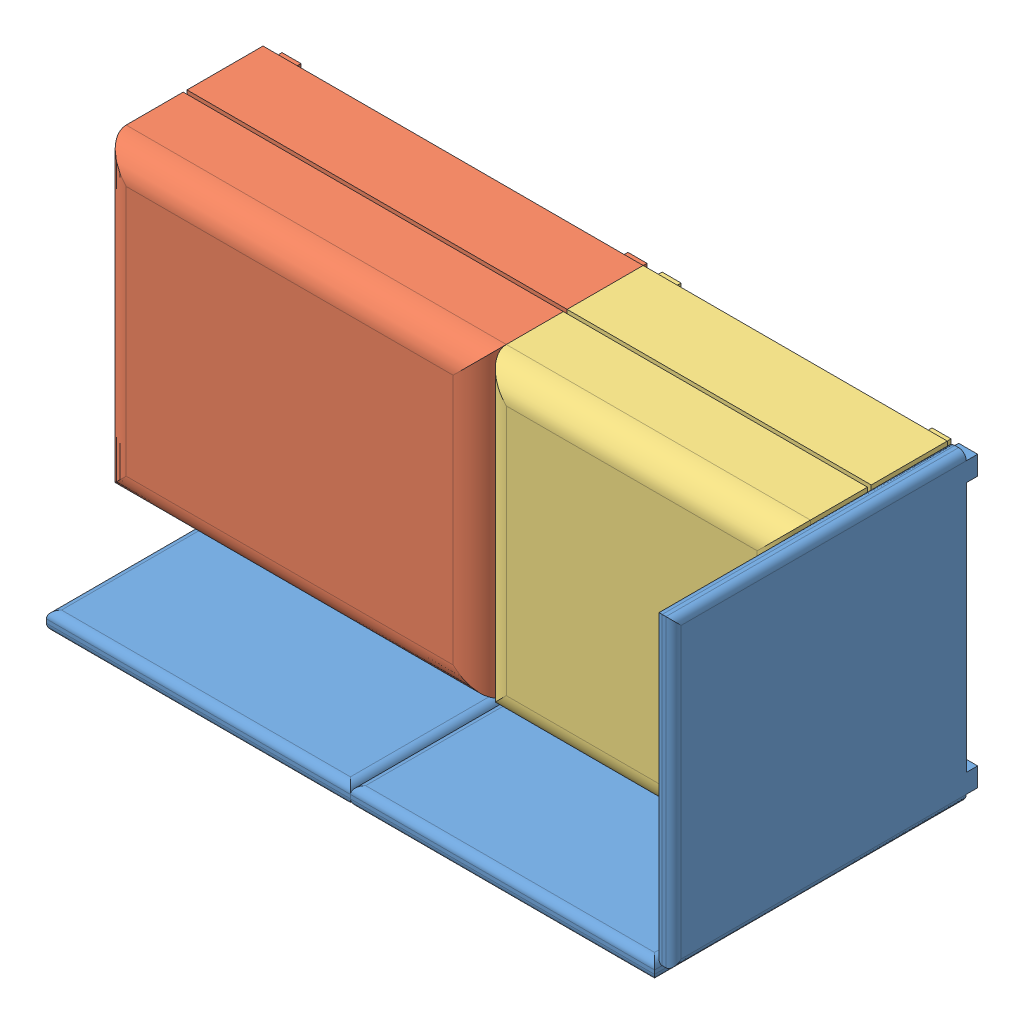
SolidWorks assembly Sofa-R, configuration Standard. Lengths in mm.
Overall size (1850 850 800).
5 component instances, 3 part files, 12 mates.
Components (placement in the parent):
- Rückenstütze-80x80-1: Rückenstütze-80x80 [Standard] at (48.0974 -746.2493 765.6126) size (800 50 800)
- Sitzelement-1: Sitzelement [Standard] at (-51.9026 -321.2493 795.6126) x (0 -1 0) z (-1 0 0) size (800 460 1000)
- Sitzelement-mit-Aufb-1: Sitzelement-mit-Aufb [Standard] at (848.0974 -321.2493 795.6126) x (1 0 0) z (0 -1 0) size (800 460 800)
- Rückenstütze-80x80-2: Rückenstütze-80x80 [Standard] at (848.0974 -746.2493 765.6126) size (800 50 800)
- Rückenstütze-80x80-3: Rückenstütze-80x80 [Standard] at (1273.0974 -321.2493 765.6126) x (0 -1 0) z (0 0 1) size (800 50 800)
Mates (geometry in assembly coordinates):
- Deckungsgleich2: coincident aligned: plane of Rückenstütze-80x80-1 through (48.0974 -746.2493 765.6126) normal (0 0 -1); plane of Sitzelement-1 through (-51.9026 -321.2493 765.6126) normal (0 0 -1)
- Deckungsgleich3: coincident aligned: plane of Rückenstütze-80x80-1 through (448.0974 -771.2493 1565.6126) normal (1 0 0); plane of Sitzelement-1 through (448.0974 78.7507 995.6126) normal (1 0 0)
- Deckungsgleich4: coincident aligned: plane of Sitzelement-1 through (-51.9026 -321.2493 765.6126) normal (0 0 -1); plane of Sitzelement-mit-Aufb-1 through (848.0974 -321.2493 765.6126) normal (0 0 -1)
- Deckungsgleich5: coincident: plane of Sitzelement-1 through (448.0974 78.7507 995.6126) normal (1 0 0); plane of Sitzelement-mit-Aufb-1 through (448.0974 -721.2493 995.6126) normal (-1 0 0)
- Deckungsgleich6: coincident aligned: plane of Sitzelement-1 through (-551.9026 78.7507 995.6126) normal (0 1 0); plane of Sitzelement-mit-Aufb-1 through (448.0974 78.7507 995.6126) normal (0 1 0)
- Deckungsgleich7: coincident aligned: plane of Sitzelement-mit-Aufb-1 through (848.0974 -321.2493 765.6126) normal (0 0 -1); plane of Rückenstütze-80x80-2 through (848.0974 -746.2493 765.6126) normal (0 0 -1)
- Deckungsgleich8: coincident aligned: plane of Sitzelement-mit-Aufb-1 through (848.0974 -321.2493 765.6126) normal (0 0 -1); plane of Rückenstütze-80x80-3 through (1273.0974 -321.2493 765.6126) normal (0 0 -1)
- Deckungsgleich10: coincident aligned: plane of Sitzelement-mit-Aufb-1 through (1248.0974 -721.2493 995.6126) normal (1 0 0); plane of Rückenstütze-80x80-2 through (1248.0974 -771.2493 1565.6126) normal (1 0 0)
- Deckungsgleich11: coincident: plane of Sitzelement-mit-Aufb-1 through (1248.0974 -721.2493 995.6126) normal (1 0 0); plane of Rückenstütze-80x80-3 through (1248.0974 58.7507 795.6126) normal (-1 0 0)
- Deckungsgleich12: coincident: plane of Sitzelement-mit-Aufb-1 through (448.0974 78.7507 995.6126) normal (0 1 0); plane of Rückenstütze-80x80-3 through (1248.0974 78.7507 1565.6126) normal (0 1 0)
- Deckungsgleich13: coincident anti-aligned: plane of Rückenstütze-80x80-1 through (-331.9026 -721.2493 795.6126) normal (0 1 0); plane of Sitzelement-1 through (-551.9026 -721.2493 995.6126) normal (0 -1 0)
- Deckungsgleich14: coincident: plane of Sitzelement-mit-Aufb-1 through (448.0974 -721.2493 995.6126) normal (0 -1 0); plane of Rückenstütze-80x80-2 through (468.0974 -721.2493 795.6126) normal (0 1 0)
